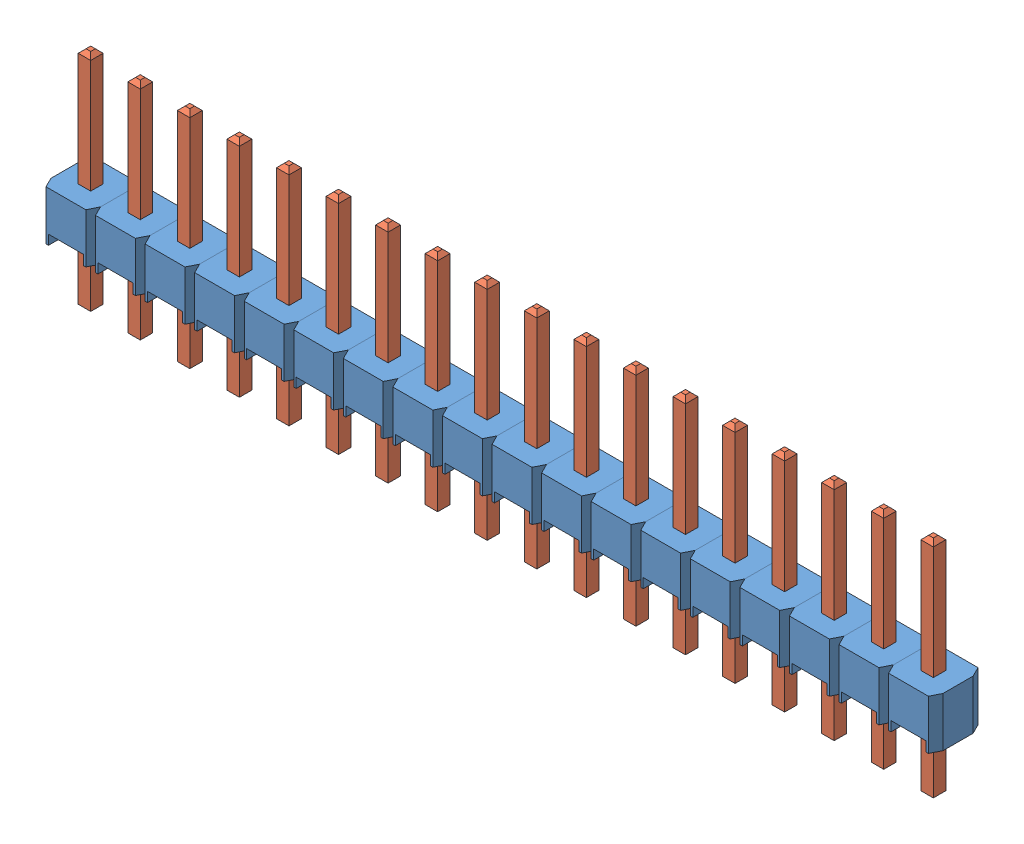
SolidWorks assembly Headers for Raykha, configuration 3pin. Lengths in mm.
Overall size (45.72 11.54 2.54).
36 component instances, 2 part files, 3 mates.
Components (placement in the parent):
- PlasticHolder-1: PlasticHolder [Default] at (0.8273 2.9943 2.6053) x (1 0 0) z (0 0 -1)
- SinglePinStraight-1: SinglePinStraight [Default] at (0.8273 -2.5457 2.6053)
- SinglePinStraight-2: SinglePinStraight [Default] at (3.3673 -2.5457 2.6053)
- PlasticHolder-2: PlasticHolder [Default] at (3.3673 2.9943 2.6053) x (1 0 0) z (0 0 -1)
- PlasticHolder-3: PlasticHolder [Default] at (5.9073 2.9943 2.6053) x (1 0 0) z (0 0 -1)
- SinglePinStraight-3: SinglePinStraight [Default] at (5.9073 -2.5457 2.6053)
- PlasticHolder-4: PlasticHolder [Default] at (8.4473 2.9943 2.6053) x (1 0 0) z (0 0 -1)
- SinglePinStraight-4: SinglePinStraight [Default] at (8.4473 -2.5457 2.6053)
- PlasticHolder-5: PlasticHolder [Default] at (10.9873 2.9943 2.6053) x (1 0 0) z (0 0 -1)
- SinglePinStraight-5: SinglePinStraight [Default] at (10.9873 -2.5457 2.6053)
- PlasticHolder-6: PlasticHolder [Default] at (13.5273 2.9943 2.6053) x (1 0 0) z (0 0 -1)
- SinglePinStraight-6: SinglePinStraight [Default] at (13.5273 -2.5457 2.6053)
- SinglePinStraight-7: SinglePinStraight [Default] at (16.0673 -2.5457 2.6053)
- PlasticHolder-7: PlasticHolder [Default] at (16.0673 2.9943 2.6053) x (1 0 0) z (0 0 -1)
- PlasticHolder-8: PlasticHolder [Default] at (18.6073 2.9943 2.6053) x (1 0 0) z (0 0 -1)
- SinglePinStraight-8: SinglePinStraight [Default] at (18.6073 -2.5457 2.6053)
- PlasticHolder-9: PlasticHolder [Default] at (21.1473 2.9943 2.6053) x (1 0 0) z (0 0 -1)
- SinglePinStraight-9: SinglePinStraight [Default] at (21.1473 -2.5457 2.6053)
- PlasticHolder-10: PlasticHolder [Default] at (23.6873 2.9943 2.6053) x (1 0 0) z (0 0 -1)
- SinglePinStraight-10: SinglePinStraight [Default] at (23.6873 -2.5457 2.6053)
- PlasticHolder-11: PlasticHolder [Default] at (26.2273 2.9943 2.6053) x (1 0 0) z (0 0 -1)
- SinglePinStraight-11: SinglePinStraight [Default] at (26.2273 -2.5457 2.6053)
- PlasticHolder-12: PlasticHolder [Default] at (28.7673 2.9943 2.6053) x (1 0 0) z (0 0 -1)
- SinglePinStraight-12: SinglePinStraight [Default] at (28.7673 -2.5457 2.6053)
- PlasticHolder-13: PlasticHolder [Default] at (31.3073 2.9943 2.6053) x (1 0 0) z (0 0 -1)
- SinglePinStraight-13: SinglePinStraight [Default] at (31.3073 -2.5457 2.6053)
- PlasticHolder-14: PlasticHolder [Default] at (33.8473 2.9943 2.6053) x (1 0 0) z (0 0 -1)
- SinglePinStraight-14: SinglePinStraight [Default] at (33.8473 -2.5457 2.6053)
- PlasticHolder-15: PlasticHolder [Default] at (36.3873 2.9943 2.6053) x (1 0 0) z (0 0 -1)
- SinglePinStraight-15: SinglePinStraight [Default] at (36.3873 -2.5457 2.6053)
- PlasticHolder-16: PlasticHolder [Default] at (38.9273 2.9943 2.6053) x (1 0 0) z (0 0 -1)
- SinglePinStraight-16: SinglePinStraight [Default] at (38.9273 -2.5457 2.6053)
- PlasticHolder-17: PlasticHolder [Default] at (41.4673 2.9943 2.6053) x (1 0 0) z (0 0 -1)
- SinglePinStraight-17: SinglePinStraight [Default] at (41.4673 -2.5457 2.6053)
- SinglePinStraight-18: SinglePinStraight [Default] at (44.0073 -2.5457 2.6053)
- PlasticHolder-18: PlasticHolder [Default] at (44.0073 2.9943 2.6053) x (1 0 0) z (0 0 -1)
Mates (geometry in assembly coordinates):
- Distance1: distance = 6 mm: plane of SinglePinStraight-1 through (0.8273 8.9943 2.6053) normal (0 1 0); plane of PlasticHolder-1 through (0.8273 2.9943 2.6053) normal (0 1 0)
- Coincident2: coincident: line of PlasticHolder-1 through (0.5073 0.9543 2.2853) axis (0 1 0); line of SinglePinStraight-1 through (0.5073 8.7943 2.2853) axis (0 -1 0)
- Coincident4: coincident: line of PlasticHolder-1 through (1.1473 0.9543 2.2853) axis (0 1 0); line of SinglePinStraight-1 through (1.1473 8.7943 2.2853) axis (0 -1 0)
